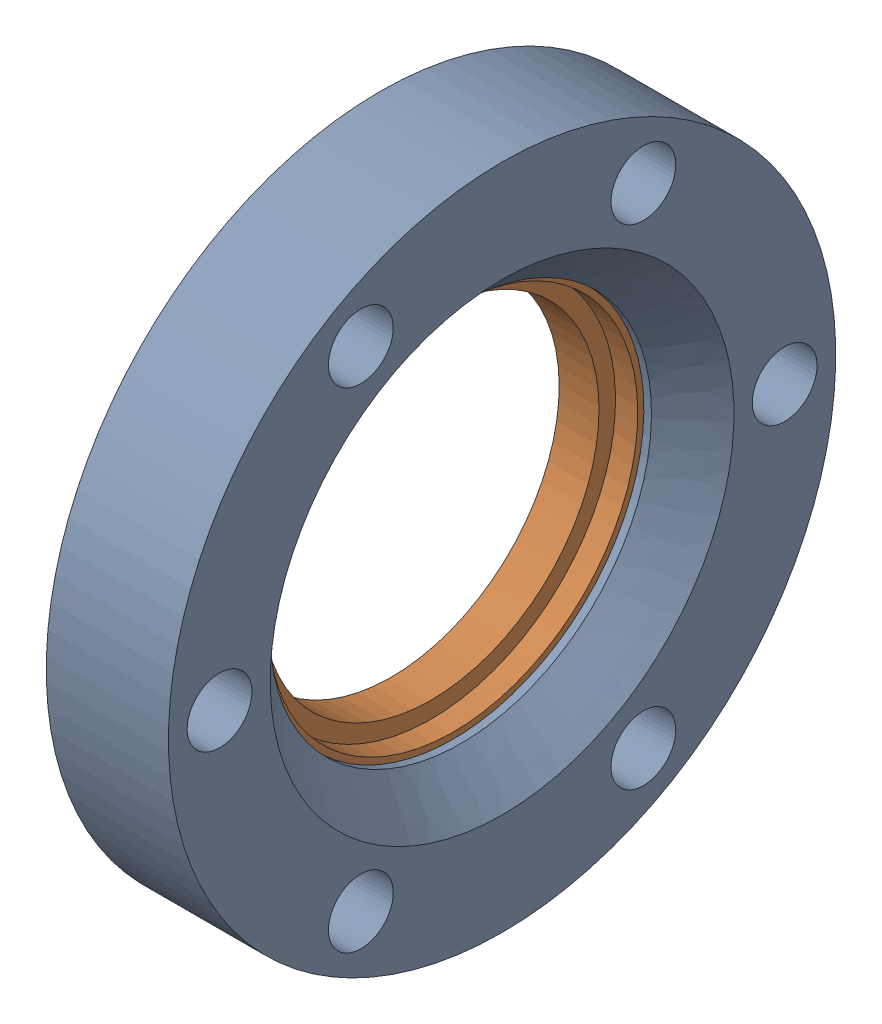
SolidWorks assembly 100014 (2.75 X 1.5 R)_2, configuration Default. Lengths in mm.
Overall size (12.7 69.34 69.34).
2 component instances, 2 part files, 0 mates.
Components (placement in the parent):
- 100014 (2.75 X 1.5 REC)_3-1: 100014 (2.75 X 1.5 REC)_3 [Default] at origin size (12.7 69.34 69.34)
- 100014 (2.75 X 1.5 INS)_2-1: 100014 (2.75 X 1.5 INS)_2 [Default] at (1.17 0 0) x (1 0 0) z (0 0.994423 -0.105464) size (6.96 48.1 48.1)
